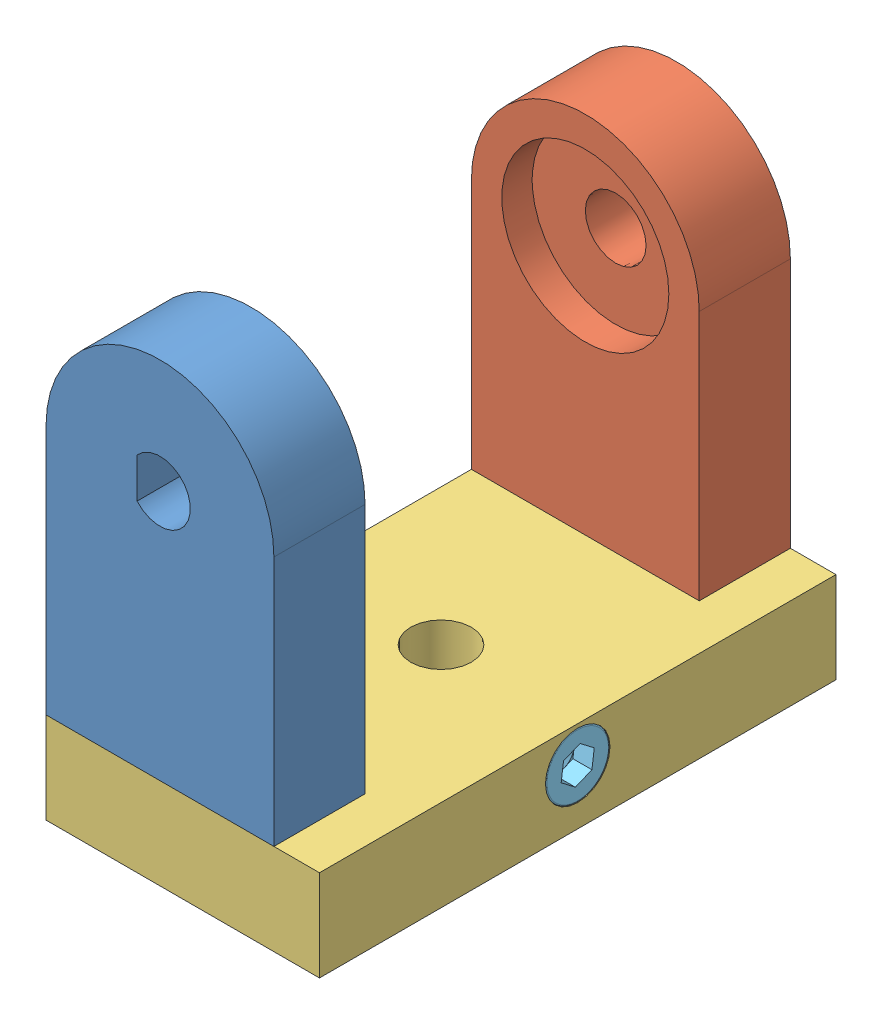
SolidWorks assembly Link6, configuration Default. Lengths in mm.
Overall size (36 60 68.86).
9 component instances, 5 part files, 1 mates.
Components (placement in the parent):
- ConnectingJoint-1: ConnectingJoint [Default] at (-13.0484 0 -9.0061) size (36 60 68.86)
  - BearingJoints-1: BearingJoints [Default] at (10.0484 39.9223 31.0061) size (30 48 12)
  - BearingJoints2-1: BearingJoints2 [Default] at (10.0484 39.9223 -12.9939) x (-1 0 0) z (0 0 -1) size (30 48 12)
  - JointBottom-1: JointBottom [Default] at (13.0484 -5.0777 9.0061) x (0 0 -1) z (1 0 0) size (68 12 36)
  - socket head cap screw_iso-1: socket head cap screw_iso [ISO 4762 M6 x 20 - 20S] at (3.0484 -5.0777 -18.9939) x (0 1 0) z (-0.488199 0 0.872732) size (26 10 10)
  - socket head cap screw_iso-2: socket head cap screw_iso [ISO 4762 M6 x 20 - 20S] at (3.0484 -5.0777 37.0061) x (0 1 0) z (0 0 1) size (26 10 10)
  - socket head cap screw_iso-3: socket head cap screw_iso [ISO 4762 M6 x 20 - 20S] at (17.0484 -5.0777 37.0061) x (0 1 0) z (0 0 1) size (26 10 10)
  - socket head cap screw_iso-4: socket head cap screw_iso [ISO 4762 M6 x 20 - 20S] at (17.0484 -5.0777 -18.9939) x (0 1 0) z (-0.513591 0 0.858035) size (26 10 10)
  - M5X10-1: M5X10 [Default] at (22.2578 2.0842 9.2195) x (-1 0 0) z (0 -0.924225 -0.381849) size (15 8.5 8.5)
Mates (geometry in assembly coordinates):
- Concentric1: concentric: cylinder of ConnectingJoint-1/JointBottom-1 through (0 -1.0777 0) axis (0 -1 0) radius 11
